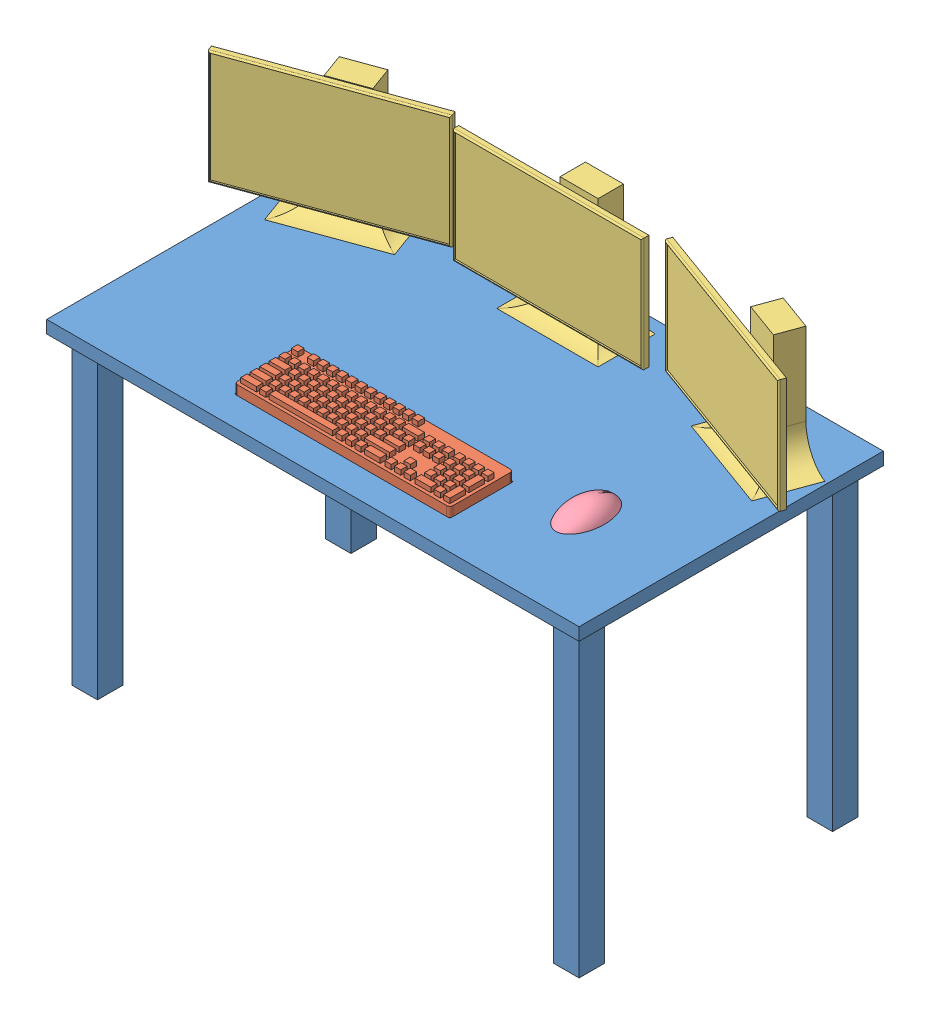
SolidWorks assembly AssembledTutorialDesk, configuration Default. Lengths in mm.
Overall size (1221.62 901.7 609.6).
6 component instances, 4 part files, 15 mates.
Components (placement in the parent):
- Table-1: Table [Default] at (-86.1739 280.7887 1057.5524) size (1066.8 635 609.6)
- Keyboard-1: Keyboard [Default] at (205.9261 914.995 1024.3683) size (431.8 29.37 127)
- Monitor-1: Monitor [Default] at (-66.3538 914.995 691.7085) x (0.939693 0 -0.34202) z (0.34202 0 0.939693) size (381 267.49 114.3)
- Monitor-2: Monitor [Default] at (320.2261 914.995 613.0524) size (381 267.49 114.3)
- Monitor-3: Monitor [Default] at (719.0604 914.995 622.21) x (0.939693 0 0.34202) z (-0.34202 0 0.939693) size (381 267.49 114.3)
- Mouse-1: Mouse [Default] at (766.3136 903.0887 879.7677) x (0 0 -1) z (1 0 0) size (133.78 41.83 84.16)
Mates (geometry in assembly coordinates):
- Coincident2: coincident anti-aligned: plane of Table-1 through (-86.1739 914.995 1024.3683) normal (0 0 -1); plane of Keyboard-1 through (205.9261 934.8387 1024.3683) normal (0 0 1)
- Coincident3: coincident anti-aligned: plane of Table-1 through (205.9261 914.995 1057.5524) normal (1 0 0); plane of Keyboard-1 through (205.9261 934.8387 1024.3683) normal (-1 0 0)
- Coincident4: coincident anti-aligned: plane of Table-1 through (-86.1739 914.995 1057.5524) normal (0 1 0); plane of Keyboard-1 through (205.9261 914.995 1024.3683) normal (0 -1 0)
- Coincident5: coincident anti-aligned: plane of Table-1 through (-201.4353 914.995 740.8742) normal (-0.34202 0 -0.939693); plane of Monitor-1 through (-66.3538 915.7887 691.7085) normal (0.34202 0 0.939693)
- Coincident6: coincident anti-aligned: plane of Table-1 through (239.8532 914.995 938.8882) normal (-0.939693 0 0.34202); plane of Monitor-1 through (124.5918 915.7887 622.21) normal (0.939693 0 -0.34202)
- Coincident7: coincident anti-aligned: plane of Table-1 through (-86.1739 914.995 1057.5524) normal (0 1 0); plane of Monitor-1 through (-66.3538 914.995 691.7085) normal (0 -1 0)
- Coincident8: coincident anti-aligned: plane of Table-1 through (-86.1739 914.995 613.0524) normal (0 0 -1); plane of Monitor-2 through (320.2261 915.7887 613.0524) normal (0 0 1)
- Coincident9: coincident anti-aligned: plane of Table-1 through (-86.1739 914.995 1057.5524) normal (0 1 0); plane of Monitor-2 through (320.2261 914.995 613.0524) normal (0 -1 0)
- Coincident10: coincident anti-aligned: plane of Table-1 through (523.4261 914.995 1057.5524) normal (-1 0 0); plane of Monitor-2 through (523.4261 915.7887 613.0524) normal (1 0 0)
- Coincident11: coincident anti-aligned: plane of Table-1 through (147.937 914.995 414.3381) normal (0.34202 0 -0.939693); plane of Monitor-3 through (719.0604 915.7887 622.21) normal (-0.34202 0 0.939693)
- Coincident12: coincident anti-aligned: plane of Table-1 through (-86.1739 914.995 1057.5524) normal (0 1 0); plane of Monitor-3 through (719.0604 914.995 622.21) normal (0 -1 0)
- Coincident13: coincident anti-aligned: plane of Table-1 through (675.8951 914.995 1334.9228) normal (-0.939693 0 -0.34202); plane of Monitor-3 through (910.006 915.7887 691.7085) normal (0.939693 0 0.34202)
- Coincident14: coincident anti-aligned: plane of Table-1 through (-86.1739 915.7887 1057.5524) normal (0 1 0); plane of Mouse-1 through (715.5136 915.7887 968.4966) normal (0 -1 0)
- Distance1: distance = 254 mm aligned: plane of Mouse-1 through (767.9011 947.5387 828.9524) normal (0 0 1); plane of Table-1 through (-111.5739 915.7887 1082.9524) normal (0 0 1)
- Distance2: distance = 190.5 mm aligned: plane of Mouse-1 through (764.7261 947.5387 828.9524) normal (1 0 0); plane of Table-1 through (955.2261 915.7887 1082.9524) normal (1 0 0)
